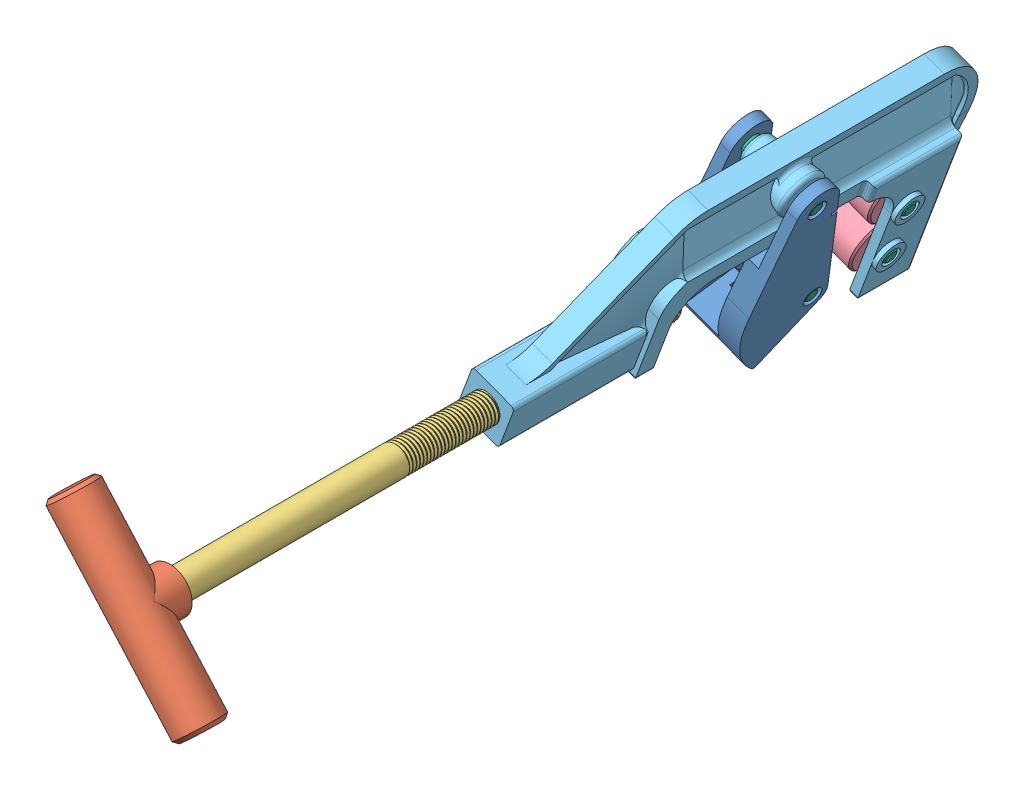
SolidWorks assembly Handle matl, configuration Default. Lengths in mm.
Overall size (92.71 126.59 463.18).
12 component instances, 7 part files, 18 mates.
Components (placement in the parent):
- Cutter support-1: Cutter support [Default] at (104.9324 19.576 -52.4224) x (0.240047 0.640694 -0.729307) z (-0.936431 0.350851 0) size (81.78 85 46)
- Handle with shaft-1: Handle with shaft [Default] at (247.8061 39.5333 317.841) x (0 0 -1) z (-0.665294 0.746581 0) size (312.5 25 110)
  - Handle-3: Handle [Default<As Welded>] at (32.7874 88.3843 67.7523) size (31 25 110)
  - Handle shaft-1: Handle shaft [Default] at (332.7874 88.3843 122.7523) x (0 0.585455 -0.810705) z (-1 0 0) size (16 18.48 300)
- Roller-1: Roller [Default] at (107.1831 48.3849 -123.2709) x (-0.012894 -0.034413 0.999325) z (-0.936431 0.350851 0) size (30 30 30)
- Frame-2: Frame [Default] at (124.7132 137.9265 -115.2709) x (-0.936431 0.350851 0) z (0 0 1) size (45 115 255.35)
- Roller-2: Roller [Default] at (89.6157 87.0034 -123.2709) x (0.301688 0.805214 -0.510504) z (0.936431 -0.350851 0) size (30 30 30)
- Spring pin-2: Spring pin [Default] at (82.5925 89.6348 -123.2709) x (0.046179 0.123254 -0.9913) z (0.936431 -0.350851 0) size (10 10 45)
- Spring pin-3: Spring pin [Default] at (72.0669 61.5418 -123.2709) x (0.050854 0.135731 -0.98944) z (0.936431 -0.350851 0) size (10 10 45)
- Cutter-1: Cutter [Default] at (95.2554 59.3029 -76.7655) x (0.936431 -0.350851 0) z (0.114408 0.30536 0.945339) size (18 32 32)
- Spring pin-4: Spring pin [Default] at (74.1857 67.197 -76.7655) x (0.123096 0.328548 -0.936431) z (0.936431 -0.350851 0) size (10 10 45)
- Spring pin-5: Spring pin [Default] at (98.3807 131.7742 -55.2709) x (0.123096 0.328548 -0.936431) z (0.936431 -0.350851 0) size (10 10 45)
Mates (geometry in assembly coordinates):
- Concentric4: concentric: cylinder of Handle with shaft-1/Handle shaft-1 through (100.1537 72.3763 285.0536) axis (0 0 -1) radius 8; cylinder of Frame-2 through (100.1537 72.3763 -5.2709) axis (0 0 1) radius 8
- Concentric5: concentric: cylinder of Cutter support-1 through (97.9125 131.9496 -55.2709) axis (0.936431 -0.350851 0) radius 5; cylinder of Frame-2 through (140.9884 115.8105 -55.2709) axis (-0.936431 0.350851 0) radius 5
- Width2: width: plane of Frame-2 through (133.4969 118.6173 -55.2709) normal (0.936431 -0.350851 0); plane of Frame-2 through (105.404 129.1428 -55.2709) normal (-0.936431 0.350851 0); plane of Cutter support-1 through (100.3548 24.4595 216.8956) normal (-0.936431 0.350851 0); plane of Cutter support-1 through (83.3782 76.0558 227.8805) normal (0.936431 -0.350851 0)
- Concentric6: concentric: cylinder of Roller-1 through (79.0902 58.9105 -123.2709) axis (0.936431 -0.350851 0) radius 5; cylinder of Frame-2 through (133.4032 38.5611 -123.2709) axis (-0.936431 0.350851 0) radius 5
- Coincident1: coincident: plane of Roller-1 through (107.1831 48.3849 -123.2709) normal (0.936431 -0.350851 0); plane of Frame-2 through (128.2342 104.5708 -95.2709) normal (-0.936431 0.350851 0)
- Concentric7: concentric: cylinder of Frame-2 through (143.9287 66.6541 -123.2709) axis (-0.936431 0.350851 0) radius 5; cylinder of Roller-2 through (117.7086 76.4779 -123.2709) axis (-0.936431 0.350851 0) radius 5
- Coincident2: coincident: plane of Frame-2 through (128.2342 104.5708 -95.2709) normal (-0.936431 0.350851 0); plane of Roller-2 through (117.7086 76.4779 -123.2709) normal (0.936431 -0.350851 0)
- Concentric9: concentric: cylinder of Frame-2 through (143.9287 66.6541 -123.2709) axis (-0.936431 0.350851 0) radius 5; cylinder of Spring pin-2 through (124.7319 73.8465 -123.2709) axis (-0.936431 0.350851 0) radius 5
- Coincident3: coincident: plane of Frame-2 through (124.7319 73.8465 -123.2709) normal (0.936431 -0.350851 0); plane of Spring pin-2 through (124.7319 73.8465 -123.2709) normal (0.936431 -0.350851 0)
- Coincident4: coincident: plane of Frame-2 through (82.5925 89.6348 -123.2709) normal (-0.936431 0.350851 0); plane of Spring pin-2 through (82.5925 89.6348 -123.2709) normal (-0.936431 0.350851 0)
- Concentric10: concentric: cylinder of Frame-2 through (133.4032 38.5611 -123.2709) axis (-0.936431 0.350851 0) radius 5; cylinder of Spring pin-3 through (114.2063 45.7536 -123.2709) axis (-0.936431 0.350851 0) radius 5
- Coincident6: coincident: plane of Frame-2 through (72.0669 61.5418 -123.2709) normal (-0.936431 0.350851 0); plane of Spring pin-3 through (72.0669 61.5418 -123.2709) normal (-0.936431 0.350851 0)
- Concentric11: concentric: cylinder of Cutter support-1 through (73.7175 67.3724 -76.7655) axis (0.936431 -0.350851 0) radius 5; cylinder of Cutter-1 through (85.1628 63.0843 -76.7655) axis (-0.936431 0.350851 0) radius 5.05
- Width4: width: plane of Cutter-1 through (103.6833 56.1452 -76.7655) normal (0.936431 -0.350851 0); plane of Cutter-1 through (86.8276 62.4605 -76.7655) normal (-0.936431 0.350851 0); plane of Cutter support-1 through (93.7998 26.9155 216.8956) normal (-0.936431 0.350851 0); plane of Cutter support-1 through (75.0712 33.9325 216.8956) normal (0.936431 -0.350851 0)
- Concentric12: concentric: cylinder of Cutter support-1 through (73.7175 67.3724 -76.7655) axis (0.936431 -0.350851 0) radius 5; cylinder of Spring pin-4 through (116.3252 51.4087 -76.7655) axis (-0.936431 0.350851 0) radius 5
- Width5: width: plane of Spring pin-4 through (116.3252 51.4087 -76.7655) normal (0.936431 -0.350851 0); plane of Spring pin-4 through (74.1857 67.197 -76.7655) normal (-0.936431 0.350851 0); plane of Cutter support-1 through (61.8565 35.7151 -52.4224) normal (-0.936431 0.350851 0); plane of Cutter support-1 through (104.9324 19.576 -52.4224) normal (0.936431 -0.350851 0)
- Concentric13: concentric: cylinder of Cutter support-1 through (97.9125 131.9496 -55.2709) axis (0.936431 -0.350851 0) radius 5; cylinder of Spring pin-5 through (140.5202 115.9859 -55.2709) axis (-0.936431 0.350851 0) radius 5
- Width6: width: plane of Spring pin-5 through (140.5202 115.9859 -55.2709) normal (0.936431 -0.350851 0); plane of Spring pin-5 through (98.3807 131.7742 -55.2709) normal (-0.936431 0.350851 0); plane of Cutter support-1 through (61.8565 35.7151 -52.4224) normal (-0.936431 0.350851 0); plane of Cutter support-1 through (104.9324 19.576 -52.4224) normal (0.936431 -0.350851 0)
